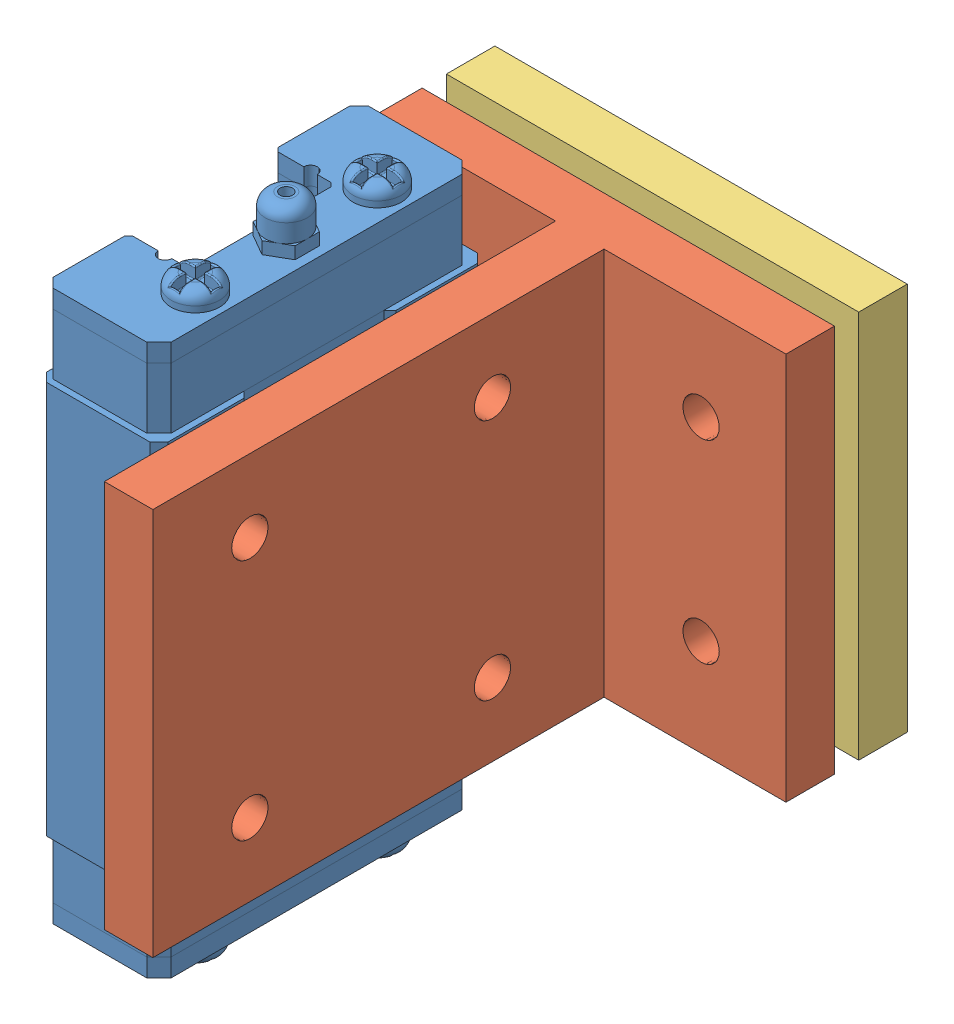
SolidWorks assembly Ползун с зажимом зеркально, configuration По умолчанию. Lengths in mm.
Overall size (34 50.47 50.2).
3 component instances, 3 part files, 12 mates.
Components (placement in the parent):
- Ползун-1: Ползун [Default] at (-13 6.5 0) x (0 0 1) z (0 1 0) size (27 10 50.47)
- Уголок-1: Уголок [По умолчанию] at (4 6.7 -18) x (0 0 1) z (-1 0 0) size (44.2 32 34)
- Прижимная планка-1: Прижимная планка [По умолчанию] at (-1.7637 -0.7936 -54.4) x (0 0 1) z (-1 0 0) size (4 32 34)
Mates (geometry in assembly coordinates):
- Совпадение1: coincident anti-aligned: plane of Ползун-1 through (-7 0 6) normal (0 -1 0); plane of assembly through (0 0 0) normal (0 1 0)
- Совпадение2: coincident aligned: plane of Ползун-1 through (0 38.9 -13.5) normal (1 0 0); plane of assembly through (0 0 0) normal (1 0 0)
- Совпадение3: coincident anti-aligned: plane of Ползун-1; plane of assembly through (0 0 0) normal (0 0 1)
- Концентричный1: concentric aligned: cylinder of Ползун-1 through (0 32.7 10) axis (1 0 0) radius 1.25; cylinder of Уголок-1 through (0 32.7 10) axis (1 0 0) radius 1.5
- Концентричный2: concentric aligned: cylinder of Ползун-1 through (0 12.7 -10) axis (1 0 0) radius 1.25; cylinder of Уголок-1 through (0 12.7 -10) axis (1 0 0) radius 1.5
- Совпадение4: coincident anti-aligned: plane of Ползун-1 through (0 38.9 -13.5) normal (1 0 0); plane of Уголок-1 through (0 6.7 -18) normal (-1 0 0)
- Параллельность1: parallel aligned: plane of Ползун-1 through (-7 45.4 6) normal (0 1 0); plane of Уголок-1 through (0 38.7 -18) normal (0 1 0)
- Концентричный4: concentric anti-aligned: cylinder of Уголок-1 through (12 30.7 -23.2) axis (0 0 1) radius 1.5; cylinder of Прижимная планка-1 through (12 30.7 -25.2) axis (0 0 -1) radius 1.5
- Концентричный5: concentric anti-aligned: cylinder of Уголок-1 through (-8 14.7 -23.2) axis (0 0 1) radius 1.5; cylinder of Прижимная планка-1 through (-8 14.7 -25.2) axis (0 0 -1) radius 1.5
- Совпадение5: coincident aligned: plane of Уголок-1 through (0 38.7 -18) normal (0 1 0); plane of Прижимная планка-1 through (19 38.7 -25.2) normal (0 1 0)
- Совпадение6: coincident aligned: plane of Уголок-1 through (19 -27.6953 -23.2) normal (1 0 0); plane of Прижимная планка-1 through (19 6.7 -25.2) normal (1 0 0)
- Совпадение7: coincident: plane of Прижимная планка-1 through (-1.7637 -0.7936 -25.2) normal (0 0 1); point of assembly
